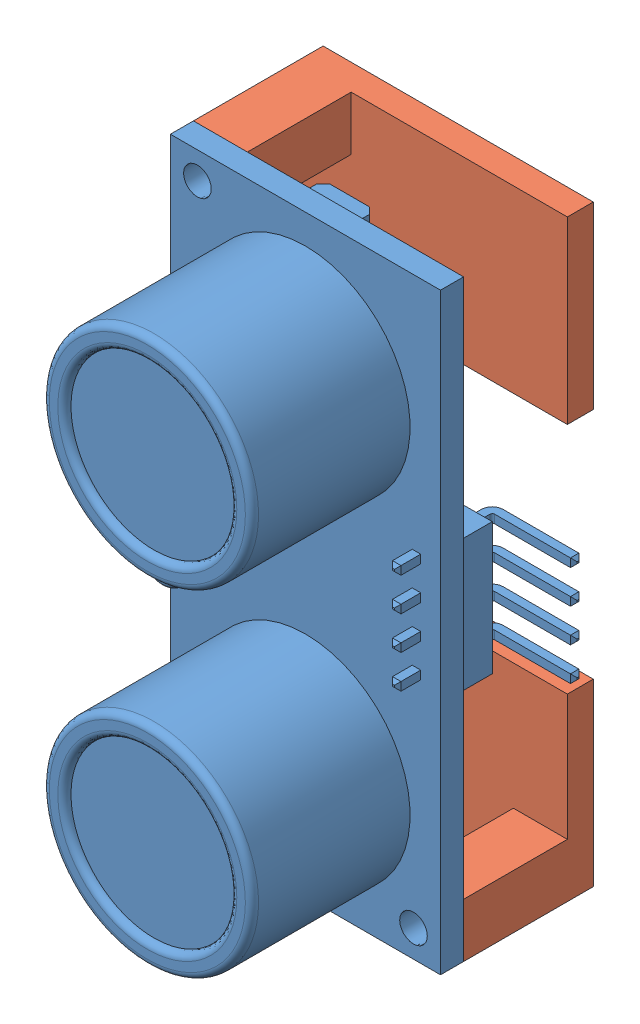
SolidWorks assembly Baugruppe2, configuration Standard. Lengths in mm.
Overall size (25.58 45.72 23.97).
2 component instances, 2 part files, 3 mates.
Components (placement in the parent):
- hc sr04 ultrasonic sensor2-1: hc sr04 ultrasonic sensor2 [Default] at (-5.0165 -19.9814 -4.7912) size (25.58 45.72 18.36)
- Teil4-2: Teil4 [Default] at (-5.0155 -19.9814 -12.7912) x (0 -1 0) z (0 0 -1) size (45.72 20.83 10)
Mates (geometry in assembly coordinates):
- Deckungsgleich28: coincident aligned: plane of hc sr04 ultrasonic sensor2-1 through (-15.4305 -42.8414 -3.0132) normal (-1 0 0); plane of Teil4-2 through (-15.4305 2.8786 -14.7912) normal (-1 0 0)
- Deckungsgleich29: coincident aligned: plane of hc sr04 ultrasonic sensor2-1 through (-15.4305 2.8786 -3.0132) normal (0 1 0); plane of Teil4-2 through (5.3995 2.8786 -14.7912) normal (0 1 0)
- Deckungsgleich31: coincident aligned: line of hc sr04 ultrasonic sensor2-1 through (5.3975 2.8786 -4.7912) axis (-1 0 0); line of Teil4-2 through (-11.2705 2.8786 -4.7912) axis (-1 0 0)
